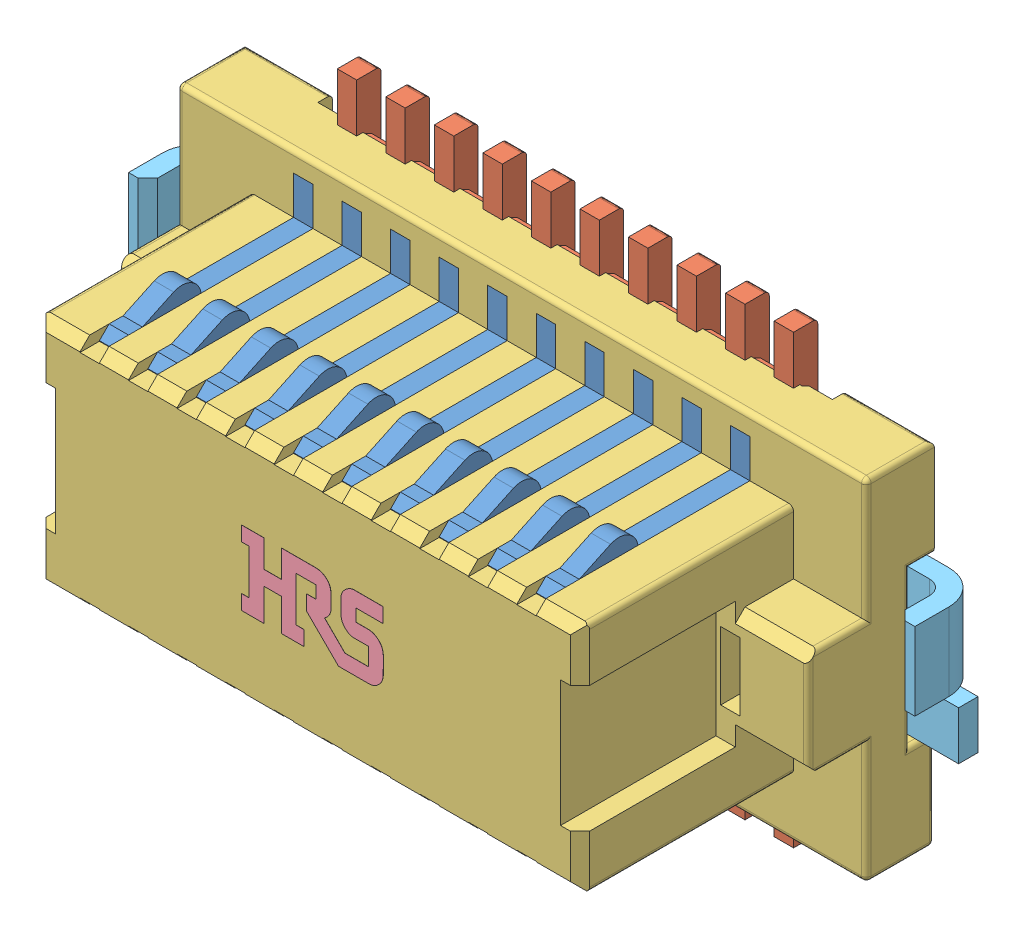
SolidWorks assembly Conn_Hirose_DF12B-20DS-0_5V_86_eec.step-1, configuration 默认. Lengths in mm.
Overall size (8.1 4.6 2.91).
5 component instances, 5 part files, 0 mates.
Components (placement in the parent):
- 1.step-1: 1.step [默认] at origin size (4.71 3.19 2.2)
- 2.step-1: 2.step [默认] at origin size (4.78 4.6 0.25)
- 3.step-1: 3.step [默认] at origin size (7.1 3.6 2.9)
- Hirose_Electric.step-1: Hirose_Electric.step [默认] at (-0.0359 -0.0489 2.8995) size (1.46 0.76 0.02)
- 4.step-1: 4.step [默认] at (-4.85 -1.5 0) size (8.1 1.5 0.7)
